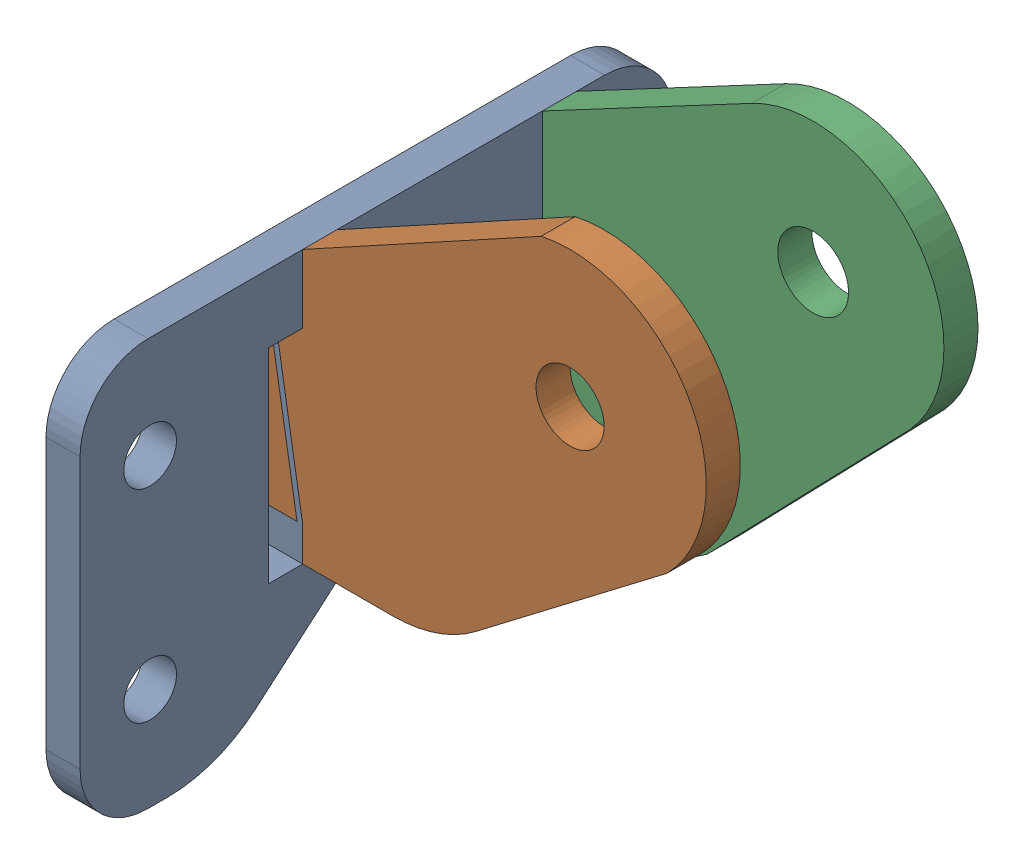
SolidWorks assembly WT-A0100-AB-Toe Bracket1, configuration Default. Lengths in mm.
Overall size (40.8 50.39 55.24).
3 component instances, 3 part files, 6 mates.
Components (placement in the parent):
- WT-FB-Toe Base Plate11-1: WT-FB-Toe Base Plate11 [Default] at (22.5935 33.4208 -28.102) size (3.17 37.93 55.25)
- WT-FB-Toe Bottom Clevis11-1: WT-FB-Toe Bottom Clevis11 [Default] at (-402.1509 25.2365 -16.926) x (1 0 0) z (0 0 -1) size (40.8 37.86 3.17)
- WT-GA-Toe Top Clevis11-1: WT-GA-Toe Top Clevis11 [Default] at (102.0031 -4.5841 -39.278) x (1 0 0) z (0 0 -1) size (40.6 42.28 3.17)
Mates (geometry in assembly coordinates):
- Coincident1: coincident: plane of WT-FB-Toe Base Plate1-1 through (25.7685 44.2865 -39.278) normal (0 0 -1); plane of WT-GA-Toe Top Clevis1-1 through (51.0037 50.246 -39.278) normal (0 0 1)
- Coincident3: coincident: plane of WT-FB-Toe Base Plate1-1 through (25.7685 25.4041 -51.9175) normal (1 0 0); plane of WT-GA-Toe Top Clevis1-1 through (25.7685 25.2365 -42.453) normal (-1 0 0)
- Coincident4: coincident: plane of WT-FB-Toe Base Plate1-1 through (22.5935 25.4041 -51.9175) normal (-1 0 0); plane of WT-FB-Toe Bottom Clevis1-1 through (22.5935 47.4615 -13.751) normal (-1 0 0)
- Coincident7: coincident: plane of WT-FB-Toe Base Plate1-1 through (25.7685 44.2865 -42.453) normal (0 -1 0); plane of WT-GA-Toe Top Clevis1-1 through (22.5935 44.2865 -42.453) normal (0 1 0)
- Coincident11: coincident: plane of WT-FB-Toe Base Plate1-1 through (25.7685 47.4615 -16.926) normal (0 0 1); plane of WT-FB-Toe Bottom Clevis1-1 through (50.6923 50.3977 -16.926) normal (0 0 -1)
- Coincident12: coincident: plane of WT-FB-Toe Base Plate1-1 through (25.7685 47.4615 -16.926) normal (0 -1 0); plane of WT-FB-Toe Bottom Clevis1-1 through (25.7685 47.4615 -13.751) normal (0 1 0)
